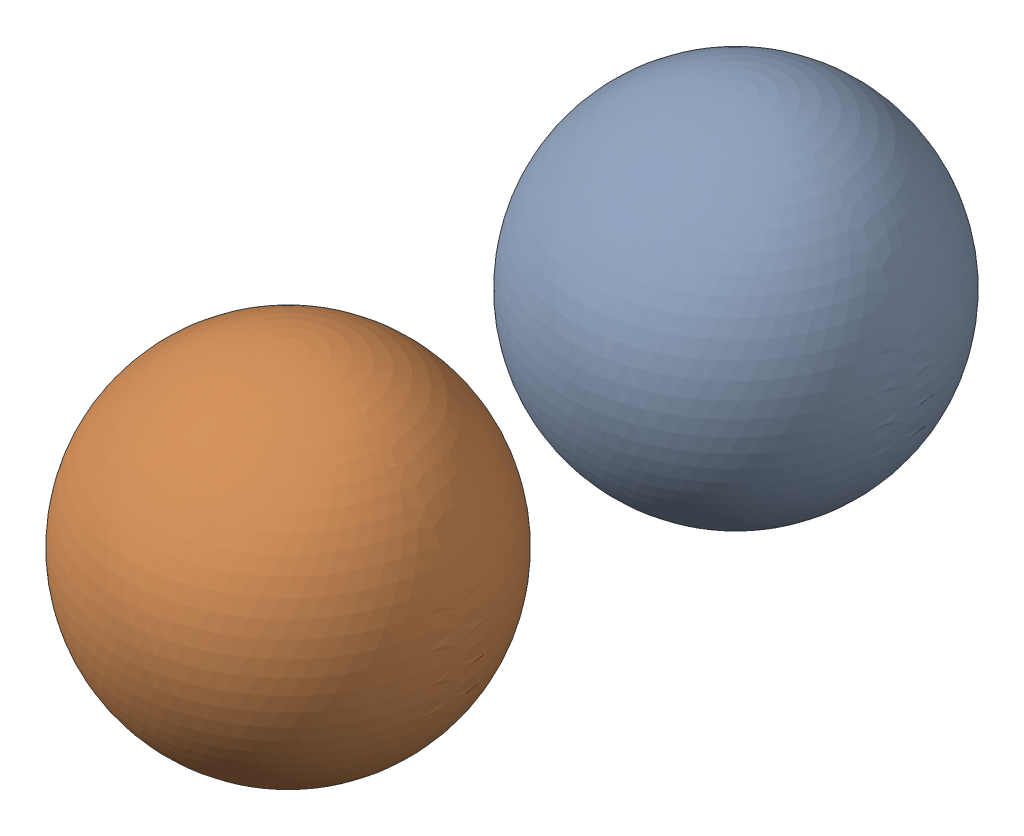
SolidWorks assembly 2-packing-disk, configuration Default. Lengths in mm.
Overall size (42.67 42.67 98.42).
2 component instances, 1 part files, 2 mates.
Components (placement in the parent):
- golf ball-1: golf ball [Default] at (0 0 -27.8765) size (42.67 42.67 42.67)
- golf ball-2: golf ball [Default] at (0 0 27.8765) size (42.67 42.67 42.67)
Mates (geometry in assembly coordinates):
- Coincident1: coincident: point of golf ball-1
- Coincident2: coincident: unknown of golf ball-2
